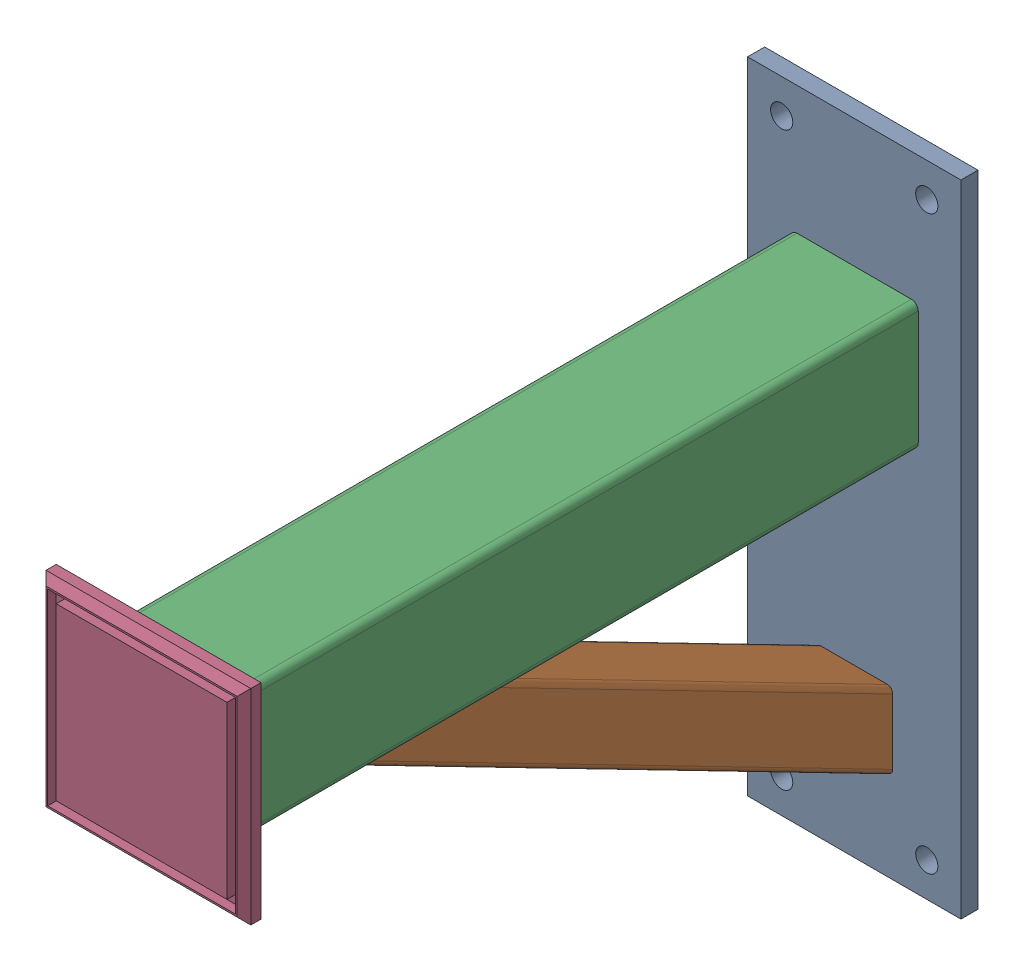
SolidWorks assembly 4А.0001.000 СБ Подставка, configuration По умолчанию. Lengths in mm.
Overall size (250 750 871.59).
4 component instances, 4 part files, 9 mates.
Components (placement in the parent):
- 4А.0001.001 Плита-1: 4А.0001.001 Плита [По умолчанию] at origin size (250 750 20)
- 4А.0001.002 Балка-1: 4А.0001.002 Балка [По умолчанию] at (0 110.5715 672.2291) x (0 -0.889288 0.457348) z (0 -0.457348 -0.889288) size (80 90 754)
- 4А.0001.003 Стойка-1: 4А.0001.003 Стойка [По умолчанию] at (0 150 20) size (150 150 815)
- 4А.0001.004 Плита-1: 4А.0001.004 Плита [По умолчанию] at (0 150 835) size (240 240 20)
Mates (geometry in assembly coordinates):
- Совпадение1: coincident anti-aligned: plane of 4А.0001.001 Плита^4А.0001.000 СБ Подставка_4А.0000.000 СБ Опора в сборе-1 through (0 0 20) normal (0 0 1); plane of 4А.0001.002 Балка^4А.0001.000 СБ Подставка_4А.0000.000 СБ Опора в сборе-1 through (60 -269.8404 20) normal (0 0 -1)
- Совпадение2: coincident anti-aligned: plane of 4А.0001.002 Балка^4А.0001.000 СБ Подставка_4А.0000.000 СБ Опора в сборе-1 through (0 110.5715 672.2291) normal (-1 0 0)
- Совпадение3: coincident anti-aligned: plane of 4А.0001.001 Плита^4А.0001.000 СБ Подставка_4А.0000.000 СБ Опора в сборе-1 through (0 0 20) normal (0 0 1); plane of 4А.0001.003 Стойка^4А.0001.000 СБ Подставка_4А.0000.000 СБ Опора в сборе-1 through (-67 83 20) normal (0 0 -1)
- Совпадение4: coincident aligned: plane of 4А.0001.003 Стойка^4А.0001.000 СБ Подставка_4А.0000.000 СБ Опора в сборе-1 through (0 150 20) normal (1 0 0)
- Расстояние1: distance = 150 mm aligned: plane of 4А.0001.003 Стойка^4А.0001.000 СБ Подставка_4А.0000.000 СБ Опора в сборе-1 through (67 225 835) normal (0 1 0); plane of 4А.0001.001 Плита^4А.0001.000 СБ Подставка_4А.0000.000 СБ Опора в сборе-1 through (125 375 20) normal (0 1 0)
- Совпадение5: coincident anti-aligned: plane of 4А.0001.002 Балка^4А.0001.000 СБ Подставка_4А.0000.000 СБ Опора в сборе-1 through (60 75 690.523) normal (0 1 0); plane of 4А.0001.003 Стойка^4А.0001.000 СБ Подставка_4А.0000.000 СБ Опора в сборе-1 through (67 75 835) normal (0 -1 0)
- Совпадение6: coincident: plane of 4А.0001.003 Стойка^4А.0001.000 СБ Подставка_4А.0000.000 СБ Опора в сборе-1 through (-67 83 835) normal (0 0 1); plane of 4А.0001.004 Плита^4А.0001.000 СБ Подставка_4А.0000.000 СБ Опора в сборе-1 through (0 150 835) normal (0 0 -1)
- Совпадение7: coincident: plane of 4А.0001.003 Стойка^4А.0001.000 СБ Подставка_4А.0000.000 СБ Опора в сборе-1 through (0 150 20) normal (0 1 0); plane of 4А.0001.004 Плита^4А.0001.000 СБ Подставка_4А.0000.000 СБ Опора в сборе-1 through (0 150 835) normal (0 1 0)
- Совпадение8: coincident aligned: plane of 4А.0001.003 Стойка^4А.0001.000 СБ Подставка_4А.0000.000 СБ Опора в сборе-1 through (0 150 20) normal (1 0 0); plane of 4А.0001.004 Плита^4А.0001.000 СБ Подставка_4А.0000.000 СБ Опора в сборе-1 through (0 150 835) normal (1 0 0)
